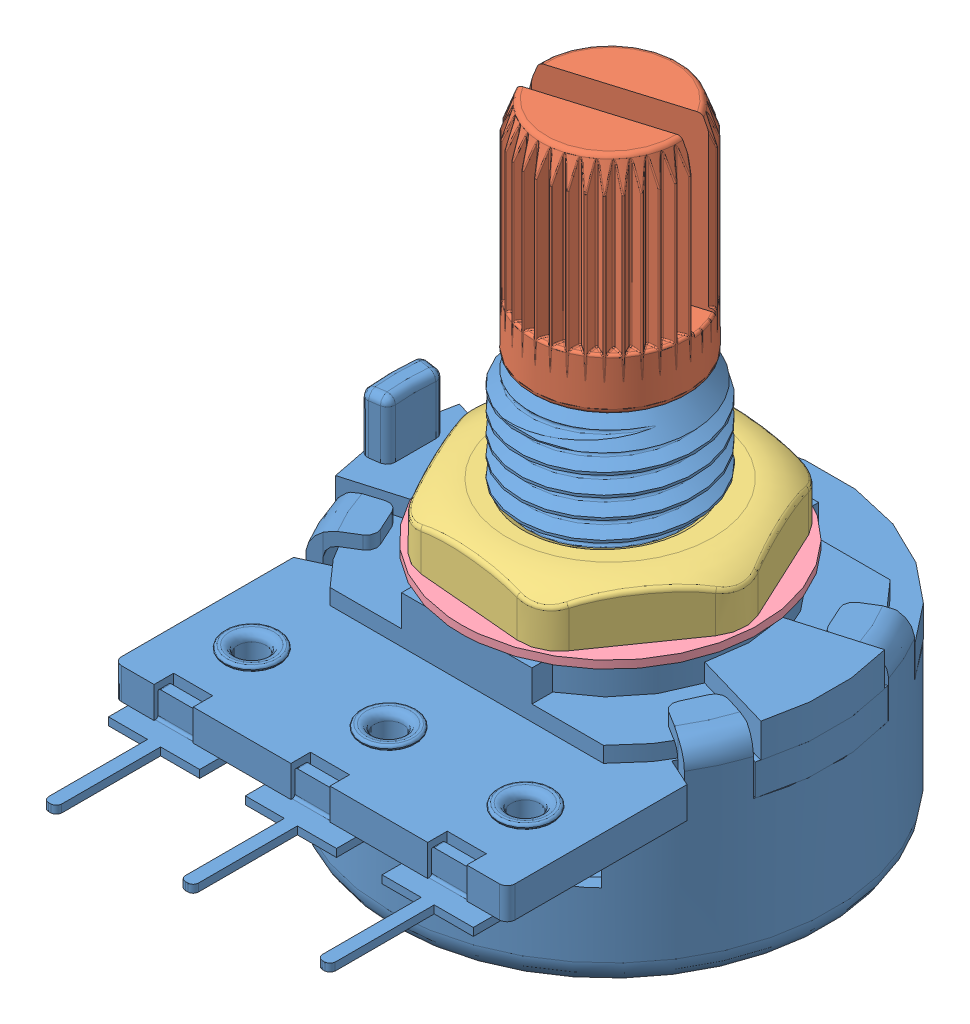
SolidWorks assembly Potentiomètre 10K, configuration Default. Lengths in mm.
Overall size (17 23.77 24.75).
4 component instances, 4 part files, 9 mates.
Components (placement in the parent):
- Potentiomètre B-1: Potentiomètre B [Default] at origin size (17 15.36 24.75)
- Potentiomètre A-1: Potentiomètre A [Default] at (0 6.5 0) x (0.289639 0 0.957136) z (-0.957136 0 0.289639) size (5.99 12.41 5.99)
- Potentiomètre Ecrou-1: Potentiomètre Ecrou [Default] at (0 0.3 0) x (0.422733 0 0.906254) z (-0.906254 0 0.422733) size (11.08 2.46 10.48)
- Potentiomètre Rondelle-1: Potentiomètre Rondelle [Default] x (0.999919 0 -0.012725) z (0.012725 0 0.999919) size (11.45 0.3 11.45)
Mates (geometry in assembly coordinates):
- Coïncidente1: coordinate: point of Potentiomètre B-1
- Coaxiale1: concentric aligned: cylinder of Potentiomètre B-1 through (0 2.5 0) axis (0 1 0) radius 1.25; cylinder of Potentiomètre A-1 through (0 2.5 0) axis (0 1 0) radius 1.25
- Coïncidente2: coincident anti-aligned: plane of Potentiomètre B-1 through (0 6.5 0) normal (0 1 0); plane of Potentiomètre A-1 through (0 6.5 0) normal (0 -1 0)
- AngleLimite2: limit planar angle = 2.847743 rad anti-aligned: plane of Potentiomètre A-1 through (4.1938 8.4 -0.6422) normal (-0.289639 0 -0.957136); plane of Potentiomètre B-1 through (-2.5 -1.2 -5.5) normal (0 0 -1)
- Coaxiale2: concentric aligned: circle of Potentiomètre B-1; circle of Potentiomètre Ecrou-1
- DistanceLimite1: limit distance = 0.3 mm anti-aligned: plane of Potentiomètre Ecrou-1 through (0 0.3 0) normal (0 -1 0); plane of Potentiomètre B-1 through (0 0 0) normal (0 1 0)
- Coaxiale3: concentric anti-aligned: cylinder of Potentiomètre B-1 through (0 -1.2 0) axis (0 1 0) radius 5.325; cylinder of Potentiomètre Rondelle-1 through (0 0.3 0) axis (0 -1 0) radius 3.6
- DistanceLimite2: limit distance = 0 mm anti-aligned: plane of Potentiomètre Rondelle-1 through (0 0 0) normal (0 -1 0); plane of Potentiomètre B-1 through (0 0 0) normal (0 1 0)
- DistanceLimite3: limit distance = 0 mm anti-aligned: plane of Potentiomètre Rondelle-1 through (0 0.3 0) normal (0 1 0); plane of Potentiomètre Ecrou-1 through (0 0.3 0) normal (0 -1 0)
